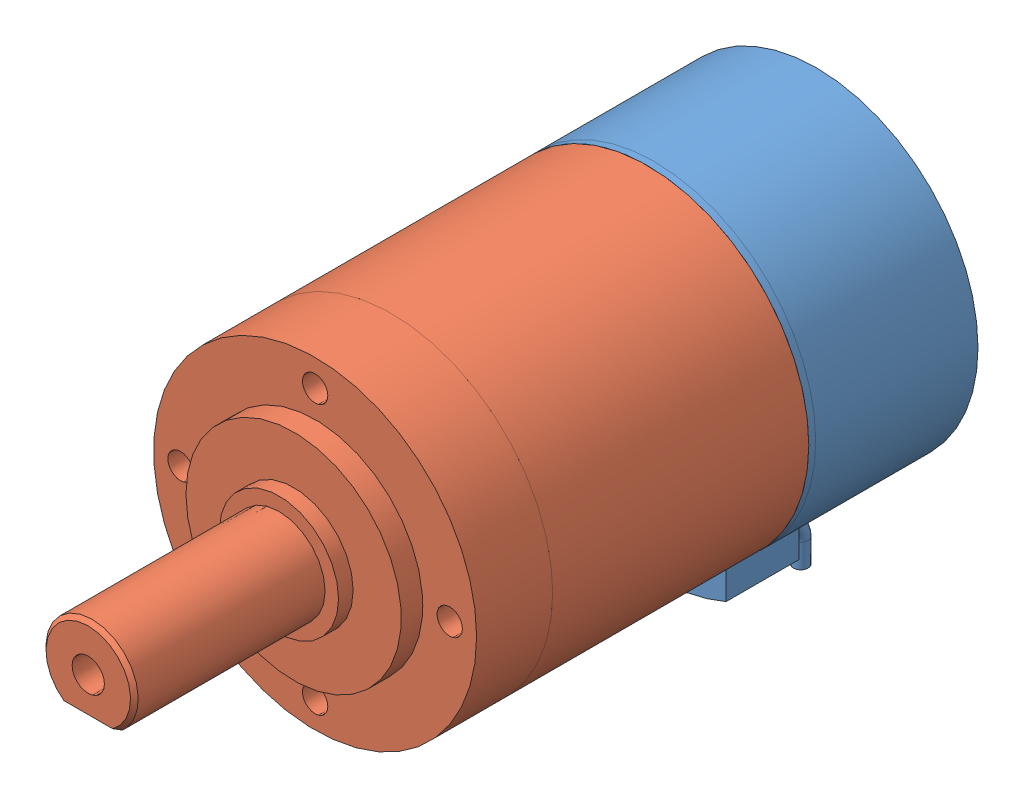
SolidWorks assembly Assemblage Moteur-réducteur Faulhaber, configuration Défaut. Lengths in mm.
Overall size (42 48.5 94.7).
2 component instances, 2 part files, 2 mates.
Components (placement in the parent):
- 4221G_BXTH _ moteur-1: 4221G_BXTH _ moteur [Défaut] at (-4.2788 3.5509 53) size (42 48.5 35)
- 42gpt-2stage_standard+KSx _ reducteur-1: 42gpt-2stage_standard+KSx _ reducteur [Défaut] at (-138.2788 3.5509 53) size (42 42.04 72.7)
Mates (geometry in assembly coordinates):
- Coaxiale1: concentric: circle of 4221G_BXTH _ moteur-1; circle of 42gpt-2stage_standard+KSx _ reducteur-1
- Coïncidente8: coincident anti-aligned: plane of 4221G_BXTH _ moteur-1 through (-4.2788 3.5509 53) normal (0 0 1); plane of 42gpt-2stage_standard+KSx _ reducteur-1 through (-4.2788 3.5509 53) normal (0 0 -1)
